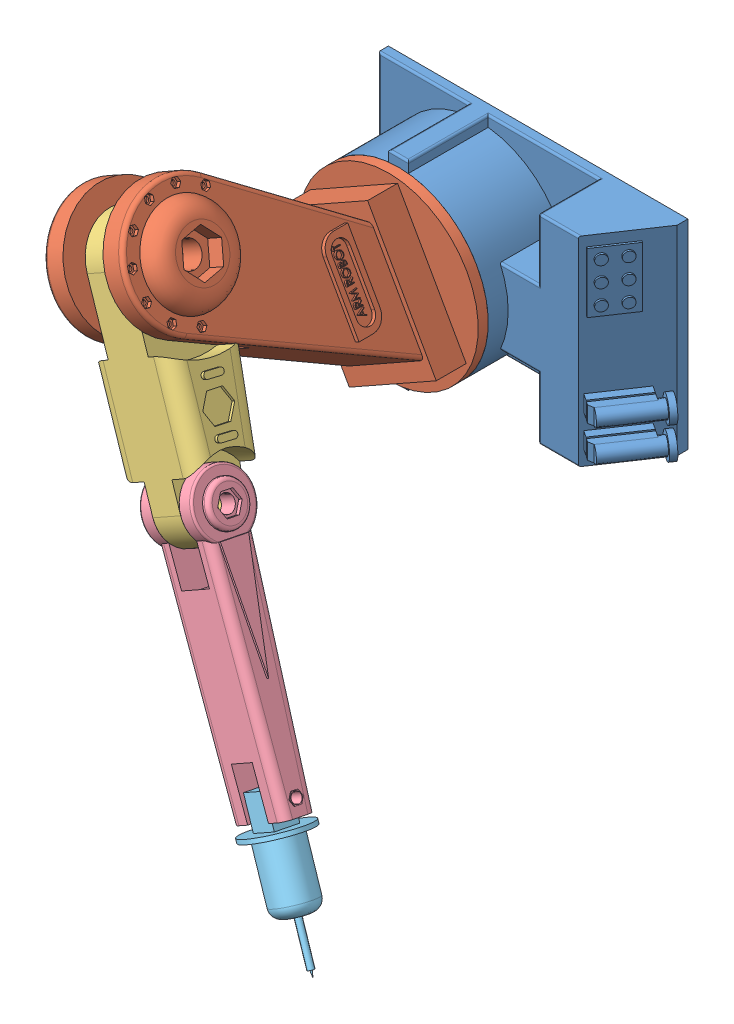
SolidWorks assembly NOP, configuration Default. Lengths in mm.
Overall size (195.52 283.61 205.44).
5 component instances, 5 part files, 8 mates.
Components (placement in the parent):
- de robot-1: de robot [Default] at origin size (160.95 100 55)
- link 1-1: link 1 [Default] at (-24.5457 43.5604 145) x (0.490914 -0.871208 0) z (0.871208 0.490914 0) size (125 130 90)
- link 2-1: link 2 [Default] at (18.6728 -33.138 163.6955) x (0.477839 -0.848005 0.229254) z (0.871208 0.490914 0) size (124.98 40 48)
- link 3-1: link 3 [Default] at (71.043 -126.0776 180.5354) x (0.484909 -0.860552 0.155925) z (0.871208 0.490914 0) size (130 30 36)
- link 4-1: link 4 [Default] at (101.3868 -179.8639 190.1552) x (0.485064 -0.860827 0.153918) z (0.871208 0.490914 0) size (70 30 30)
Mates (geometry in assembly coordinates):
- Concentric17: concentric aligned: cylinder of de robot-1 through (0 0 55) axis (0 0 -1) radius 10; cylinder of link 1-1 through (0 0 55) axis (0 0 -1) radius 10
- Coincident17: coincident anti-aligned: plane of de robot-1 through (0 0 45) normal (0 0 1); plane of link 1-1 through (0 0 45) normal (0 0 -1)
- Concentric18: concentric aligned: cylinder of link 1-1 through (-26.7237 42.3331 145) axis (-0.871208 -0.490914 0) radius 6; cylinder of link 2-1 through (0.2837 57.5515 145) axis (-0.871208 -0.490914 0) radius 6
- Coincident18: coincident anti-aligned: plane of link 1-1 through (-44.0226 54.6998 92.0938) normal (0.871208 0.490914 0); plane of link 2-1 through (-34.5646 37.9149 145) normal (-0.871208 -0.490914 0)
- Concentric19: concentric aligned: cylinder of link 2-1 through (43.5022 -19.1469 163.6955) axis (-0.871208 -0.490914 0) radius 4; cylinder of link 3-1 through (31.7409 -25.7743 163.6955) axis (-0.871208 -0.490914 0) radius 4
- Coincident21: coincident anti-aligned: plane of link 2-1 through (25.6425 -29.2107 163.6955) normal (0.871208 0.490914 0); plane of link 3-1 through (25.6425 -29.2107 163.6955) normal (-0.871208 -0.490914 0)
- Concentric20: concentric anti-aligned: cylinder of link 3-1 through (86.7248 -117.2412 180.5354) axis (-0.871208 -0.490914 0) radius 2.5; cylinder of link 4-1 through (58.0021 -133.426 180.5354) axis (0.871208 0.490914 0) radius 2.5
- Coincident22: coincident anti-aligned: plane of link 3-1 through (13.4455 -36.0835 163.6955) normal (0.871208 0.490914 0); plane of link 4-1 through (63.1796 -124.3448 185.7712) normal (-0.871208 -0.490914 0)
